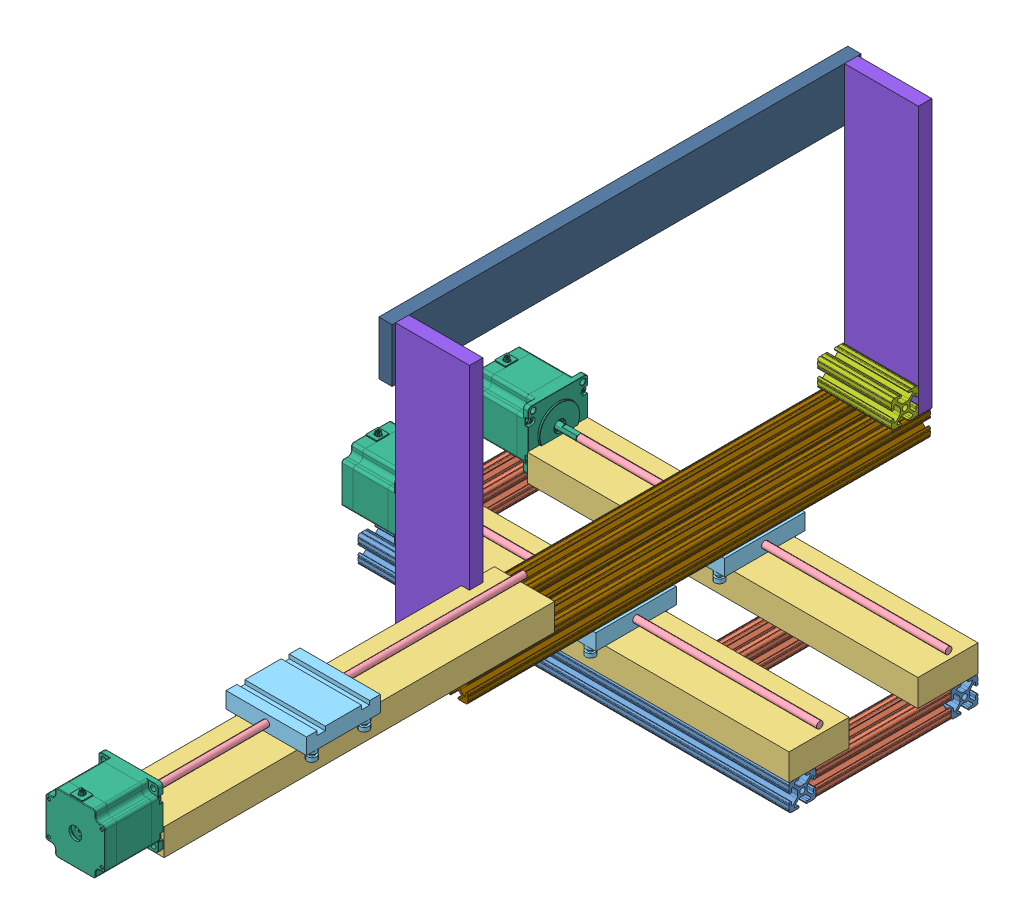
SolidWorks assembly Gantry Set up, configuration Default. Lengths in mm.
Overall size (425.03 345.44 835.14).
29 component instances, 10 part files, 32 mates.
Components (placement in the parent):
- base structure-1: base structure [Default] at origin size (408.43 25.4 179.07)
  - base bar-1: base bar [Default<As Machined>] at origin size (408.43 25.4 25.4)
  - base bar-2: base bar [Default<As Machined>] at (0 0 153.67) size (408.43 25.4 25.4)
  - connecting bars-1: connecting bars [Default<As Machined>] at (-395.732 0 12.7) x (0 0 -1) z (0 1 0) size (128.27 25.4 25.4)
  - connecting bars-2: connecting bars [Default<As Machined>] at (-139.7 0 12.7) x (0 0 -1) z (-1 0 0) size (128.27 25.4 25.4)
  - connecting bars-3: connecting bars [Default<As Machined>] at (-268.732 0 12.7) x (0 0 -1) z (0 1 0) size (128.27 25.4 25.4)
  - connecting bars-4: connecting bars [Default<As Machined>] at (-12.7 0 12.7) x (0 0 -1) z (0 1 0) size (128.27 25.4 25.4)
- Linear Actuator-1: Linear Actuator [Default] at (-370 12.7 109.37) x (0 0 1) z (-1 0 0) size (76.2 65.62 425.03)
  - rail-1: rail [Default] at origin size (57 25.4 370)
  - rod-1: rod [Default] at (27.9 33.02 -370.026) x (0.229354 0.973343 0) z (0 0 1) size (6.35 6.35 349.43)
  - slider-1: slider [Default] at (-10.2 40.64 -195.9279) x (0 0 1) z (-1 0 0) size (70 25.4 76.2)
  - stepper motor_NEMA 23-1: stepper motor_NEMA 23 [Default] at (27.9 33.02 0) x (1 0 0) z (0 0 -1) size (56.41 60.81 75.6)
- Linear Actuator-2: Linear Actuator [Default] at (-370 12.7 -12.7) x (0 0 1) z (-1 0 0) size (76.2 65.62 425.03)
  - rail-1: rail [Default] at origin size (57 25.4 370)
  - rod-1: rod [Default] at (27.9 33.02 -370.026) x (0.229354 0.973343 0) z (0 0 1) size (6.35 6.35 349.43)
  - slider-1: slider [Default] at (-10.2 40.64 -195.9279) x (0 0 1) z (-1 0 0) size (70 25.4 76.2)
  - stepper motor_NEMA 23-1: stepper motor_NEMA 23 [Default] at (27.9 33.02 0) x (1 0 0) z (0 0 -1) size (56.41 60.81 75.6)
- support piece-1: support piece [Default<As Machined>] at (-173.9681 91.44 269.858) size (70.1 25.4 25.4)
- support piece-2: support piece [Default<As Machined>] at (-173.9681 91.44 -117.492) size (70.1 25.4 25.4)
- side-bar 6061 aluminum-1: side-bar 6061 aluminum [Default] at (-173.9681 332.74 -130.192) x (0 0 -1) z (1 0 0) size (12.7 254 70.1)
- side-bar 6061 aluminum-2: side-bar 6061 aluminum [Default] at (-244.0721 332.74 282.558) x (0 0 1) z (-1 0 0) size (12.7 254 70.1)
- connection piece-2: connection piece [Default<As Machined>] at (-230.1021 66.04 -142.892) x (0 0 -1) z (0 -1 0) size (438.15 25.4 25.4)
- connection piece-3: connection piece [Default<As Machined>] at (-188.0421 66.04 -142.892) x (0 0 -1) z (0 1 0) size (438.15 25.4 25.4)
- back-bar 6061 aluminum-1: back-bar 6061 aluminum [Default] at (-256.7721 281.94 298.433) x (1 0 0) z (0 -1 0) size (12.7 444.5 50.8)
- Linear Actuator-3: Linear Actuator [Default] at (-181.5509 122.8277 634.0764) size (76.2 65.62 425.03)
  - rail-1: rail [Default] at origin size (57 25.4 370)
  - rod-1: rod [Default] at (27.9 33.02 -370.026) x (0.229354 0.973343 0) z (0 0 1) size (6.35 6.35 349.43)
  - slider-1: slider [Default] at (-10.2 40.64 -195.9279) x (0 0 1) z (-1 0 0) size (70 25.4 76.2)
  - stepper motor_NEMA 23-1: stepper motor_NEMA 23 [Default] at (27.9 33.02 0) x (1 0 0) z (0 0 -1) size (56.41 60.81 75.6)
Mates (geometry in assembly coordinates):
- Coincident1: coordinate: point of base structure-1
- Coincident2: coincident anti-aligned: plane of base structure-1/base bar-1 through (-408.432 12.7 -6.3331) normal (0 1 0); plane of Linear Actuator-2/rail-1 through (0 12.7 -12.7) normal (0 -1 0)
- Coincident4: coincident anti-aligned: plane of base structure-1/base bar-2 through (-408.432 12.7 147.3369) normal (0 1 0); plane of Linear Actuator-1/rail-1 through (0 12.7 109.37) normal (0 -1 0)
- Parallel1: parallel: line of base structure-1/base bar-1 through (0 12.7 -6.3331) axis (0 0 -1); plane of Linear Actuator-2/rail-1 through (0 12.7 -12.7) normal (1 0 0)
- Coincident8: coincident aligned: plane of base structure-1/base bar-1 through (0 -7.6708 -1.7093) normal (1 0 0); plane of Linear Actuator-2/rail-1 through (0 12.7 -12.7) normal (1 0 0)
- Coincident9: coincident aligned: plane of base structure-1/base bar-1 through (-408.432 9.5504 -12.7) normal (0 0 -1); plane of Linear Actuator-2/rail-1 through (0 12.7 -12.7) normal (0 0 -1)
- Parallel3: parallel anti-aligned: line of base structure-1/base bar-2 through (0 12.7 163.2204) axis (0 0 -1); line of Linear Actuator-1/rail-1 through (0 12.7 109.37) axis (0 0 1)
- Coincident11: coincident aligned: plane of base structure-1/base bar-2 through (0 -7.6708 151.9607) normal (1 0 0); plane of Linear Actuator-1/rail-1 through (0 12.7 109.37) normal (1 0 0)
- Coincident12: coincident aligned: plane of base structure-1/base bar-2 through (-408.432 6.3331 166.37) normal (0 0 1); plane of Linear Actuator-1/rail-1 through (0 12.7 166.37) normal (0 0 1)
- Coincident23: coincident anti-aligned: plane of support piece-2 through (-244.0721 85.1069 -130.192) normal (0 0 -1); plane of side-bar 6061 aluminum-1 through (-173.9681 78.74 -130.192) normal (0 0 1)
- Coincident24: coincident aligned: plane of support piece-2 through (-244.0721 83.7692 -119.2013) normal (-1 0 0); plane of side-bar 6061 aluminum-1 through (-244.0721 78.74 -130.192) normal (-1 0 0)
- Coincident26: coincident anti-aligned: plane of support piece-1 through (-244.0721 97.7731 282.558) normal (0 0 1); plane of side-bar 6061 aluminum-2 through (-244.0721 78.74 282.558) normal (0 0 -1)
- Coincident27: coincident aligned: plane of support piece-1 through (-173.9681 83.7692 268.1487) normal (1 0 0); plane of side-bar 6061 aluminum-2 through (-173.9681 78.74 282.558) normal (1 0 0)
- Coincident31: coincident anti-aligned: plane of Linear Actuator-1/slider-1 through (-174.0721 53.34 99.17) normal (0 1 0); plane of connection piece-2 through (-223.769 53.34 295.258) normal (0 -1 0)
- Distance4: distance = 1.27 mm aligned: plane of connection piece-2 through (-242.8021 59.7069 295.258) normal (-1 0 0); plane of Linear Actuator-1/slider-1 through (-244.0721 38.1 99.17) normal (-1 0 0)
- Distance5: distance = 119.888 mm aligned: plane of connection piece-2 through (-237.7729 67.7493 295.258) normal (0 0 1); plane of Linear Actuator-1/slider-1 through (-174.0721 38.1 175.37) normal (0 0 1)
- Coincident34: coincident anti-aligned: plane of Linear Actuator-1/slider-1 through (-174.0721 53.34 99.17) normal (0 1 0); plane of connection piece-3 through (-181.709 53.34 295.258) normal (0 -1 0)
- Distance6: distance = 1.27 mm aligned: plane of Linear Actuator-1/slider-1 through (-174.0721 38.1 99.17) normal (1 0 0); plane of connection piece-3 through (-175.3421 56.4896 295.258) normal (1 0 0)
- Distance7: distance = 119.888 mm aligned: plane of connection piece-3 through (-180.3713 64.3307 295.258) normal (0 0 1); plane of Linear Actuator-1/slider-1 through (-174.0721 38.1 175.37) normal (0 0 1)
- Coincident37: coincident anti-aligned: plane of support piece-1 through (-244.0721 78.74 260.3076) normal (0 -1 0); plane of connection piece-2 through (-220.5517 78.74 295.258) normal (0 1 0)
- Coincident38: coincident anti-aligned: plane of side-bar 6061 aluminum-2 through (-244.0721 78.74 282.558) normal (0 -1 0); plane of connection piece-3 through (-194.3753 78.74 295.258) normal (0 1 0)
- Coincident41: coincident aligned: plane of side-bar 6061 aluminum-2 through (-244.0721 78.74 295.258) normal (0 0 1); plane of connection piece-3 through (-180.3713 64.3307 295.258) normal (0 0 1)
- Coincident42: coincident anti-aligned: plane of support piece-2 through (-244.0721 78.74 -127.0424) normal (0 -1 0); plane of connection piece-2 through (-236.4352 78.74 295.258) normal (0 1 0)
- Coincident43: coincident anti-aligned: plane of side-bar 6061 aluminum-1 through (-173.9681 78.74 -130.192) normal (0 -1 0); plane of connection piece-2 through (-236.4352 78.74 295.258) normal (0 1 0)
- Coincident44: coincident aligned: plane of side-bar 6061 aluminum-1 through (-173.9681 78.74 -142.892) normal (0 0 -1); plane of connection piece-2 through (-237.7729 67.7493 -142.892) normal (0 0 -1)
- Distance10: distance = 1.27 mm aligned: plane of side-bar 6061 aluminum-2 through (-244.0721 78.74 282.558) normal (-1 0 0); plane of connection piece-2 through (-242.8021 75.5904 295.258) normal (-1 0 0)
- Distance11: distance = 1.27 mm aligned: plane of support piece-2 through (-244.0721 83.7692 -119.2013) normal (-1 0 0); plane of connection piece-2 through (-242.8021 75.5904 295.258) normal (-1 0 0)
- Coincident50: coincident: plane of side-bar 6061 aluminum-1 through (-244.0721 78.74 -130.192) normal (-1 0 0); plane of back-bar 6061 aluminum-1 through (-244.0721 281.94 -145.4294) normal (1 0 0)
- Parallel5: parallel: plane of side-bar 6061 aluminum-2 through (-244.0721 78.74 282.558) normal (-1 0 0); plane of back-bar 6061 aluminum-1 through (-244.0721 281.94 -145.4294) normal (1 0 0)
- Coincident52: coincident: plane of side-bar 6061 aluminum-2 through (-244.0721 332.74 282.558) normal (0 1 0); plane of back-bar 6061 aluminum-1 through (-256.7721 332.74 -145.4294) normal (0 1 0)
- Coincident53: coincident: plane of side-bar 6061 aluminum-1 through (-173.9681 332.74 -130.192) normal (0 1 0); plane of back-bar 6061 aluminum-1 through (-256.7721 332.74 -145.4294) normal (0 1 0)
- Distance12: distance = 3.175 mm aligned: plane of side-bar 6061 aluminum-2 through (-244.0721 78.74 295.258) normal (0 0 1); plane of back-bar 6061 aluminum-1 through (-256.7721 281.94 298.433) normal (0 0 1)
